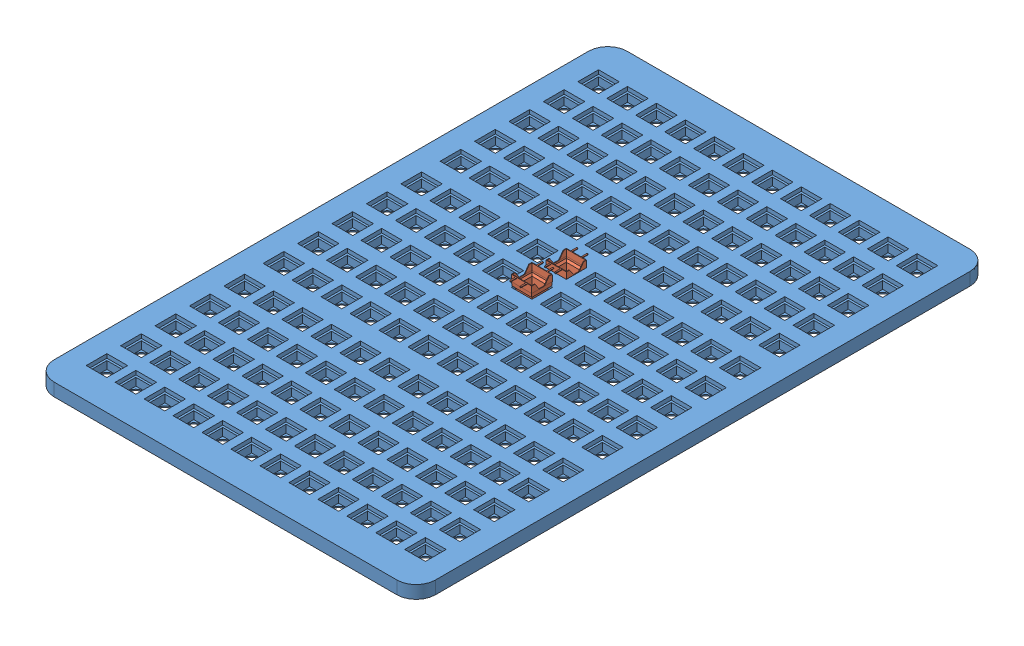
SolidWorks assembly Assem1, configuration Default. Lengths in mm.
Overall size (597 42.13 897).
3 component instances, 2 part files, 0 mates.
Components (placement in the parent):
- dense-tray-1: dense-tray [Default] at (-186.1033 -0.7229 237.3603) size (597 20.1 897)
- cup-006-1: cup-006 [Default] at (-75.4918 27.3145 -56.8908) x (0.008726 0.008727 -0.999924) z (-0.999962 0 -0.008727) size (51 34 32)
- cup-006-2: cup-006 [Default] at (-43.6981 19.2654 -78.7397) x (0 0 1) z (1 0 0) size (51 34 32)
